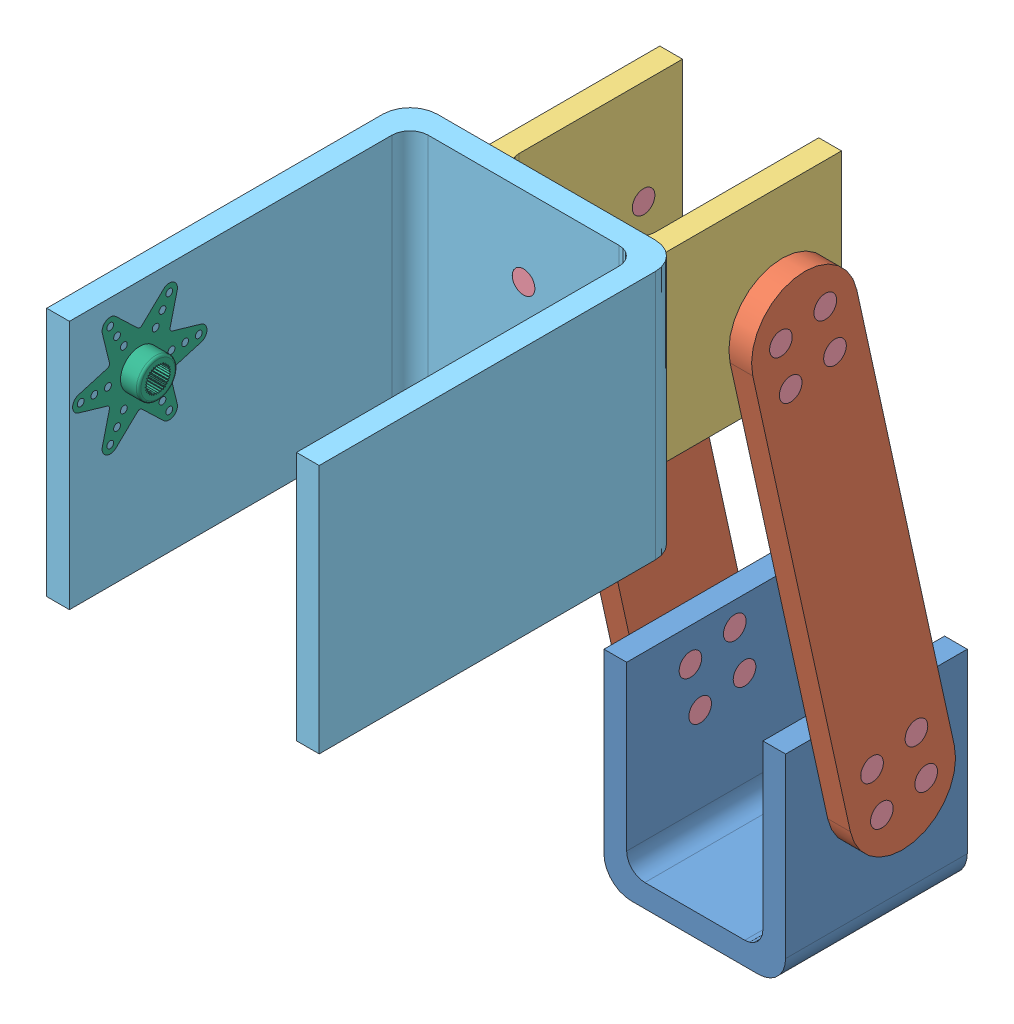
SolidWorks assembly Neck_mount, configuration Valor predeterminado. Lengths in mm.
Overall size (60 168.24 156.2).
25 component instances, 6 part files, 55 mates.
Components (placement in the parent):
- U_fix1-2: U_fix1 [Valor predeterminado] at origin size (40 45.01 40)
- Neck_support-2: Neck_support [Valor predeterminado] at (-20 -0.5489 -27.4769) x (1 0 0) z (0 -0.214896 0.976637) size (5 123.43 23.43)
- U_fix2-2: U_fix2 [Valor predeterminado] at (-20 111.368 52.7005) x (1 0 0) z (0 1 0) size (40 45 40)
- Neck_support-3: Neck_support [Valor predeterminado] at (25 -0.5489 -27.4769) x (1 0 0) z (0 -0.214896 0.976637) size (5 123.43 23.43)
- Neck_pin-1: Neck_pin [Valor predeterminado] at (15 118.7108 14.1235) x (0 -0.001296 -0.999999) z (1 0 0) size (5 5 10)
- Neck_pin-4: Neck_pin [Valor predeterminado] at (-25 128.4772 16.2725) x (0 -0.628436 -0.777861) z (1 0 0) size (5 5 10)
- Neck_pin-5: Neck_pin [Valor predeterminado] at (15 126.3282 26.0388) x (0 -0.628436 -0.777861) z (1 0 0) size (5 5 10)
- Neck_pin-6: Neck_pin [Valor predeterminado] at (15 116.5619 23.8899) x (0 -0.628436 -0.777861) z (1 0 0) size (5 5 10)
- Neck_pin-8: Neck_pin [Valor predeterminado] at (-25 35.0805 5.961) x (0 -0.628436 -0.777861) z (1 0 0) size (5 5 10)
- Neck_pin-9: Neck_pin [Valor predeterminado] at (-25 25.3142 3.812) x (0 -0.628436 -0.777861) z (1 0 0) size (5 5 10)
- Neck_pin-10: Neck_pin [Valor predeterminado] at (-25 27.4631 -5.9544) x (0 -0.628436 -0.777861) z (1 0 0) size (5 5 10)
- Neck_pin-11: Neck_pin [Valor predeterminado] at (-25 118.7108 14.1235) x (0 -0.628436 -0.777861) z (1 0 0) size (5 5 10)
- Neck_pin-12: Neck_pin [Valor predeterminado] at (-25 116.5619 23.8899) x (0 -0.628436 -0.777861) z (1 0 0) size (5 5 10)
- Neck_pin-13: Neck_pin [Valor predeterminado] at (-25 126.3282 26.0388) x (0 -0.628436 -0.777861) z (1 0 0) size (5 5 10)
- Neck_pin-14: Neck_pin [Valor predeterminado] at (15 35.0805 5.961) x (0 -0.628436 -0.777861) z (1 0 0) size (5 5 10)
- Neck_pin-15: Neck_pin [Valor predeterminado] at (15 25.3142 3.812) x (0 -0.628436 -0.777861) z (1 0 0) size (5 5 10)
- Neck_pin-16: Neck_pin [Valor predeterminado] at (-25 37.2295 -3.8054) x (0 -0.628436 -0.777861) z (1 0 0) size (5 5 10)
- Neck_pin-17: Neck_pin [Valor predeterminado] at (15 27.4631 -5.9544) x (0 -0.628436 -0.777861) z (1 0 0) size (5 5 10)
- Neck_pin-18: Neck_pin [Valor predeterminado] at (15 37.2295 -3.8054) x (0 -0.628436 -0.777861) z (1 0 0) size (5 5 10)
- Neck_pin-19: Neck_pin [Valor predeterminado] at (15 128.4772 16.2725) x (0 -0.628436 -0.777861) z (1 0 0) size (5 5 10)
- U_fix3-1: U_fix3 [Valor predeterminado] at (-30 158.868 52.7005) x (1 0 0) z (0 -1 0) size (60 80 55)
- Neck_pin-20: Neck_pin [Valor predeterminado] at (0 121.368 57.7005) x (-0.732963 -0.680269 0) z (0 0 -1) size (5 5 10)
- Neck_pin-21: Neck_pin [Valor predeterminado] at (0 141.368 57.7005) x (-0.50166 -0.865065 0) z (0 0 -1) size (5 5 10)
- Servo_star-1: Servo_star [Default] at (-27.5 142.1168 117.2128) x (0 0.500081 -0.865979) z (1 0 0) size (26.52 30 6.7)
- Servo_star-2: Servo_star [Default] at (0.0006 0 0.001) x (0.500081 0 0.865979) z (0 -1 0) size (26.52 30 6.7)
Mates (geometry in assembly coordinates):
- Coincidente5: coincident: plane of assembly; plane of assembly; plane of U_fix1-2 through (-20 42.5 20) normal (-1 0 0); plane of Neck_support-2 through (-20 -0.5489 -27.4769) normal (1 0 0)
- Coincidente6: coincident: circle of assembly; circle of assembly; circle of U_fix1-2; circle of Neck_support-2
- Coincidente7: coincident: circle of assembly; circle of assembly; circle of U_fix1-2; circle of Neck_support-2
- Coincidente8: coincident: plane of assembly; plane of assembly; plane of Neck_support-2 through (-20 -0.5489 -27.4769) normal (1 0 0); plane of U_fix2-2 through (-20 151.368 52.7005) normal (-1 0 0)
- Coincidente10: coincident: circle of assembly; circle of assembly; circle of Neck_support-2; circle of U_fix2-2
- Coincidente11: coincident: circle of assembly; circle of assembly; circle of Neck_support-2; circle of U_fix2-2
- Coincidente12: coincident: plane of assembly; plane of assembly; plane of U_fix1-2 through (20 42.5 20) normal (1 0 0); plane of Neck_support-3 through (20 -0.5489 -27.4769) normal (-1 0 0)
- Coincidente13: coincident: circle of assembly; circle of assembly; circle of U_fix1-2; circle of Neck_support-3
- Coincidente14: coincident: circle of assembly; circle of assembly; circle of U_fix2-2; circle of Neck_support-3
- Concêntrico1: concentric: cylinder of assembly; cylinder of assembly; cylinder of Neck_support-3 through (20 118.7108 14.1235) axis (1 0 0) radius 2.5; cylinder of Neck_pin-1 through (25 118.7108 14.1235) axis (-1 0 0) radius 2.5
- Coincidente15: coincident: circle of assembly; circle of assembly; circle of Neck_support-3; circle of Neck_pin-1
- Concêntrico3: concentric: cylinder of assembly; cylinder of assembly; cylinder of Neck_support-3 through (20 126.3282 26.0388) axis (1 0 0) radius 2.5; cylinder of Neck_pin-5 through (25 126.3282 26.0388) axis (-1 0 0) radius 2.5
- Concêntrico4: concentric: cylinder of assembly; cylinder of assembly; cylinder of Neck_support-3 through (20 116.5619 23.8899) axis (1 0 0) radius 2.5; cylinder of Neck_pin-6 through (25 116.5619 23.8899) axis (-1 0 0) radius 2.5
- Concêntrico5: concentric: cylinder of assembly; cylinder of assembly; cylinder of Neck_support-2 through (-25 128.4772 16.2725) axis (1 0 0) radius 2.5; cylinder of Neck_pin-4 through (-15 128.4772 16.2725) axis (-1 0 0) radius 2.5
- Concêntrico6: concentric: cylinder of assembly; cylinder of assembly; cylinder of Neck_support-2 through (-25 118.7108 14.1235) axis (1 0 0) radius 2.5; cylinder of Neck_pin-11 through (-15 118.7108 14.1235) axis (-1 0 0) radius 2.5
- Concêntrico7: concentric: cylinder of assembly; cylinder of assembly; cylinder of Neck_support-2 through (-25 116.5619 23.8899) axis (1 0 0) radius 2.5; cylinder of Neck_pin-12 through (-15 116.5619 23.8899) axis (-1 0 0) radius 2.5
- Concêntrico8: concentric: cylinder of assembly; cylinder of assembly; cylinder of Neck_support-2 through (-25 126.3282 26.0388) axis (1 0 0) radius 2.5; cylinder of Neck_pin-13 through (-15 126.3282 26.0388) axis (-1 0 0) radius 2.5
- Concêntrico9: concentric: cylinder of assembly; cylinder of assembly; cylinder of Neck_support-3 through (20 37.2295 -3.8054) axis (1 0 0) radius 2.5; cylinder of Neck_pin-18 through (25 37.2295 -3.8054) axis (-1 0 0) radius 2.5
- Concêntrico10: concentric: cylinder of assembly; cylinder of assembly; cylinder of Neck_support-3 through (20 27.4631 -5.9544) axis (1 0 0) radius 2.5; cylinder of Neck_pin-17 through (25 27.4631 -5.9544) axis (-1 0 0) radius 2.5
- Concêntrico11: concentric: cylinder of assembly; cylinder of assembly; cylinder of Neck_support-3 through (20 35.0805 5.961) axis (1 0 0) radius 2.5; cylinder of Neck_pin-14 through (25 35.0805 5.961) axis (-1 0 0) radius 2.5
- Concêntrico12: concentric: cylinder of assembly; cylinder of assembly; cylinder of Neck_support-3 through (20 25.3142 3.812) axis (1 0 0) radius 2.5; cylinder of Neck_pin-15 through (25 25.3142 3.812) axis (-1 0 0) radius 2.5
- Concêntrico13: concentric: cylinder of assembly; cylinder of assembly; cylinder of Neck_support-2 through (-25 37.2295 -3.8054) axis (1 0 0) radius 2.5; cylinder of Neck_pin-16 through (-15 37.2295 -3.8054) axis (-1 0 0) radius 2.5
- Concêntrico14: concentric: cylinder of assembly; cylinder of assembly; cylinder of Neck_support-2 through (-25 27.4631 -5.9544) axis (1 0 0) radius 2.5; cylinder of Neck_pin-10 through (-15 27.4631 -5.9544) axis (-1 0 0) radius 2.5
- Concêntrico15: concentric: cylinder of assembly; cylinder of assembly; cylinder of Neck_support-2 through (-25 25.3142 3.812) axis (1 0 0) radius 2.5; cylinder of Neck_pin-9 through (-15 25.3142 3.812) axis (-1 0 0) radius 2.5
- Concêntrico16: concentric: cylinder of assembly; cylinder of assembly; cylinder of Neck_support-2 through (-25 35.0805 5.961) axis (1 0 0) radius 2.5; cylinder of Neck_pin-8 through (-15 35.0805 5.961) axis (-1 0 0) radius 2.5
- Coincidente16: coincident: circle of assembly; circle of assembly; circle of Neck_support-3; circle of Neck_pin-6
- Coincidente17: coincident: circle of assembly; circle of assembly; circle of Neck_support-3; circle of Neck_pin-5
- Concêntrico17: concentric: cylinder of assembly; cylinder of assembly; cylinder of Neck_support-3 through (20 128.4772 16.2725) axis (1 0 0) radius 2.5; cylinder of Neck_pin-19 through (25 128.4772 16.2725) axis (-1 0 0) radius 2.5
- Coincidente21: coincident: circle of assembly; circle of assembly; circle of Neck_support-3; circle of Neck_pin-19
- Coincidente22: coincident: circle of assembly; circle of assembly; circle of U_fix2-2; circle of Neck_pin-4
- Coincidente23: coincident: circle of assembly; circle of assembly; circle of U_fix2-2; circle of Neck_pin-11
- Coincidente24: coincident: circle of assembly; circle of assembly; circle of U_fix2-2; circle of Neck_pin-13
- Coincidente25: coincident: circle of assembly; circle of assembly; circle of U_fix2-2; circle of Neck_pin-12
- Coincidente26: coincident: circle of assembly; circle of assembly; circle of Neck_support-2; circle of Neck_pin-16
- Coincidente27: coincident: circle of assembly; circle of assembly; circle of Neck_support-2; circle of Neck_pin-10
- Coincidente29: coincident: circle of assembly; circle of assembly; circle of Neck_support-2; circle of Neck_pin-8
- Coincidente30: coincident: circle of assembly; circle of assembly; circle of Neck_support-2; circle of Neck_pin-9
- Coincidente31: coincident: circle of assembly; circle of assembly; circle of U_fix1-2; circle of Neck_pin-14
- Coincidente34: coincident: circle of assembly; circle of assembly; circle of Neck_support-3; circle of Neck_pin-15
- Coincidente35: coincident: circle of assembly; circle of assembly; circle of Neck_support-3; circle of Neck_pin-17
- Coincidente36: coincident: circle of assembly; circle of assembly; circle of Neck_support-3; circle of Neck_pin-18
- Coincidente37: coincident: plane of assembly; plane of assembly; plane of U_fix2-2 through (20 151.368 52.7005) normal (0 0 1); plane of U_fix3-1 through (30 103.868 52.7005) normal (0 0 -1)
- Concêntrico18: concentric: cylinder of assembly; cylinder of assembly; cylinder of U_fix2-2 through (0 141.368 47.7005) axis (0 0 1) radius 2.5; cylinder of U_fix3-1 through (0 141.368 57.7005) axis (0 0 -1) radius 2.5
- Concêntrico19: concentric: cylinder of assembly; cylinder of assembly; cylinder of U_fix2-2 through (0 121.368 47.7005) axis (0 0 1) radius 2.5; cylinder of U_fix3-1 through (0 121.368 57.7005) axis (0 0 -1) radius 2.5
- Concêntrico20: concentric: cylinder of assembly; cylinder of assembly; cylinder of U_fix3-1 through (0 141.368 57.7005) axis (0 0 -1) radius 2.5; cylinder of Neck_pin-21 through (0 141.368 47.7005) axis (0 0 1) radius 2.5
- Coincidente38: coincident: circle of assembly; circle of assembly; circle of U_fix2-2; circle of Neck_pin-21
- Concêntrico21: concentric: cylinder of assembly; cylinder of assembly; cylinder of U_fix3-1 through (0 121.368 57.7005) axis (0 0 -1) radius 2.5; cylinder of Neck_pin-20 through (0 121.368 47.7005) axis (0 0 1) radius 2.5
- Coincidente39: coincident: circle of assembly; circle of assembly; circle of U_fix3-1; circle of Neck_pin-20
- Coincidente40: coordinate: point of assembly; point of U_fix1-2; point of assembly
- Coincidente41: coincident: plane of assembly; plane of assembly; plane of U_fix3-1 through (-27.5 133.6185 117.2128) normal (1 0 0); plane of Servo_star-1 through (-27.5 137.8664 124.5732) normal (-1 0 0)
- Coincidente42: coincident: plane of assembly; plane of assembly; plane of U_fix3-1 through (-25 144.0372 103.6503) normal (0 -0.95997 0.280102); plane of Servo_star-1 through (-25 144.053 103.7071) normal (0 0.95997 -0.280102)
- Concêntrico22: concentric: cylinder of assembly; cylinder of assembly; cylinder of U_fix3-1 through (-25 142.118 104.2128) axis (-1 0 0) radius 0.75; cylinder of Servo_star-1 through (-25 142.118 104.2128) axis (-1 0 0) radius 0.75
- Coincidente43: coincident: plane of assembly; plane of assembly; plane of U_fix1-2 through (-8.4995 0 0.0001) normal (0 -1 0); plane of Servo_star-2 through (-4.2499 0 -7.3593) normal (0 1 0)
- Coincidente44: coincident: plane of assembly; plane of assembly; plane of U_fix1-2 through (12.6639 -2.5 -5.0772) normal (-0.722625 0 -0.691241); plane of Servo_star-2 through (12.7052 -2.5 -5.1192) normal (0.722625 0 0.691241)
- Concêntrico24: concentric: cylinder of assembly; cylinder of assembly; cylinder of U_fix1-2 through (11.2583 -2.5 -6.5) axis (0 1 0) radius 0.75; cylinder of Servo_star-2 through (11.2583 -2.5 -6.5) axis (0 1 0) radius 0.75
